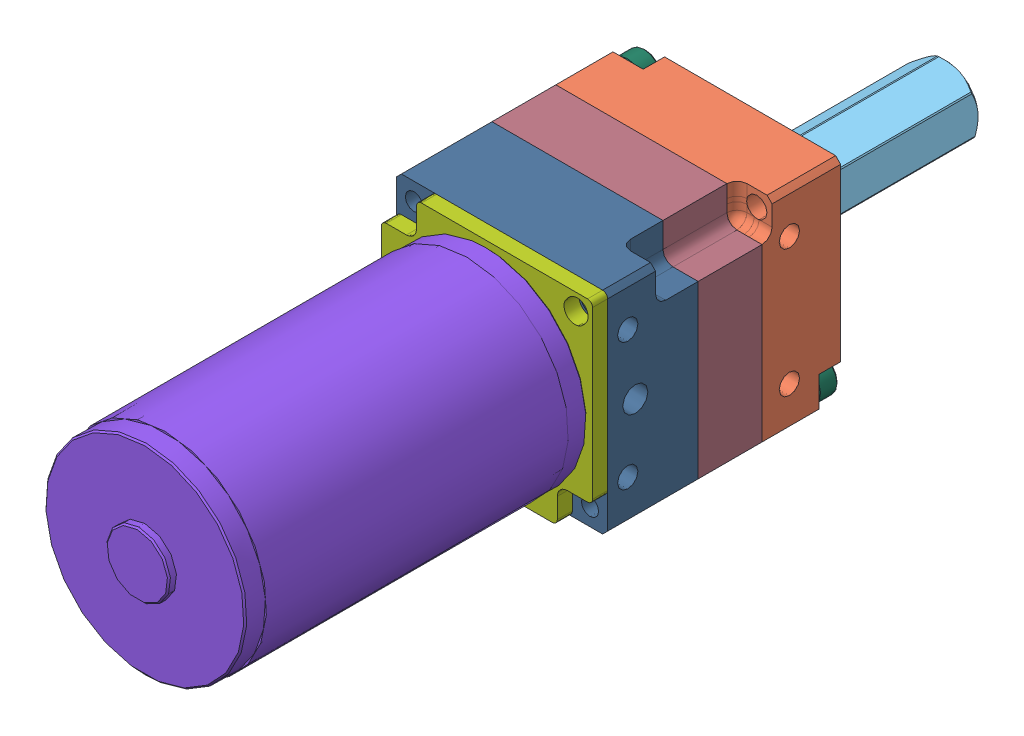
SolidWorks assembly VersaPlanetary_v1_Single_Stage_10_1_with_BAG, configuration Default. Lengths in mm.
Overall size (62.06 62.06 160.81).
22 component instances, 15 part files, 0 mates.
Components (placement in the parent):
- 217-2742-001 Rev4-1: 217-2742-001 Rev4 [Default] at (0 0 -19.9002) x (0 0 1) z (-1 0 0) size (7 28 28)
- 217-2742-001 Rev4-2: 217-2742-001 Rev4 [Default] at (0 0 -28.305) x (0 0 1) z (-0.819238 -0.573454 0) size (7 28 28)
- 217-2625-002 Rev1-1: 217-2625-002 Rev1 [Default] at (0 0 -6.2) x (-1 0 0) z (0 0 1) size (42 42 17.13)
- 217-2625-018 Rev1_98541A410-1: 217-2625-018 Rev1_98541A410 [Default] at (0 0 -12.4002) x (0 0 -1) z (0.980859 -0.194721 0) size (1 19.6 17.4)
- 217-2625-017 Rev1_9714K61-1: 217-2625-017 Rev1_9714K61 [Default] at (0 0 -20.9002) x (-0.695225 0.718792 0) z (-0.718792 -0.695225 0) size (28.51 4.98 30.18)
- Ouput Shafts^VersaPlanetary_500 Hex-1: Ouput Shafts^VersaPlanetary_500 Hex [Default] at (0 0 -20.5526) x (-0.995515 -0.094608 0) z (0 0 -1) size (17 17 64.12)
  - 217-2625-003 Rev1-1: 217-2625-003 Rev1 [Default] at origin size (17 17 64.12)
- 217-3564-000 Rev1_BAG-1: 217-3564-000 Rev1_BAG [Default] at (0 0 18) size (42 42 81.5)
  - 217-2625-011 Rev1-1: 217-2625-011 Rev1 [Default] at (0 0 -5.25) x (1 0 0) z (0 -1 0) size (8.01 7.5 7.94)
  - 217-2822-003 Rev4-1: 217-2822-003 Rev4 [Default] at (0 0 1.5) size (42 42 4.8)
  - 217-3351-1: 217-3351 [Default] at (0 0 3) x (0 1 0) z (0 0 -1) size (40.4 40.4 81.5)
- Input Housing^VersaPlanetary-1: Input Housing^VersaPlanetary [Default] at (-18.5 13.6657 1) x (0 0 -1) z (-0.885621 0.464408 0) size (20 56.7 56.7)
  - PINL-M020-006-S-1: PINL-M020-006-S [Default] at origin size (6 2 2)
  - 217-2625-001 Rev1-1: 217-2625-001 Rev1 [Default] at (-9.5 3.511 -22.7304) x (0 -0.464408 -0.885621) z (-1 0 0) size (42 42 18)
  - 217-2625-009 Rev1-1: 217-2625-009 Rev1 [Default] at (-6.02 3.511 -22.7304) x (0 0.885621 -0.464408) z (1 0 0) size (18 18 13)
  - SSS1032-0125ZB_94105A824-1: SSS1032-0125ZB_94105A824 [Default] at (-11.495 6.7192 -16.6126) x (-0.636804 0.682837 -0.35807) z (0 0.464408 0.885621) size (4.83 4.84 3.3)
- 217-2816 Rev1-1: 217-2816 Rev1 [Default] at (0 0 -6.35) x (1 0 0) z (0 0 -1) size (42 42 14.5)
  - 217-2816-001 Rev1-1: 217-2816-001 Rev1 [Default] at origin size (42 42 14.5)
- 217-2817 Rev1-1: 217-2817 Rev1 [Default] at (0 0 -10.8) x (-0.517538 0.85566 0) z (0 0 -1) size (21.94 21.95 12.7)
  - 217-2724-001 Rev1_Sun_Driver01-1: 217-2724-001 Rev1_Sun_Driver01 [Default] at (0 0 -6.375) x (0.984808 0.173648 0) z (0 0 1) size (18.94 18.95 12.7)
- SSA_SSA0832-1250ZC-1: SSA_SSA0832-1250ZC [Default] at (-17.5 17.5 -24.061) x (0.699203 0.714923 0) z (-0.714923 0.699203 0) size (6.73 35.81 6.73)
- SSA_SSA0832-1250ZC-2: SSA_SSA0832-1250ZC [Default] at (17.5 -17.5 -24.061) x (-0.999999 0.001665 0) z (-0.001665 -0.999999 0) size (6.73 35.81 6.73)
